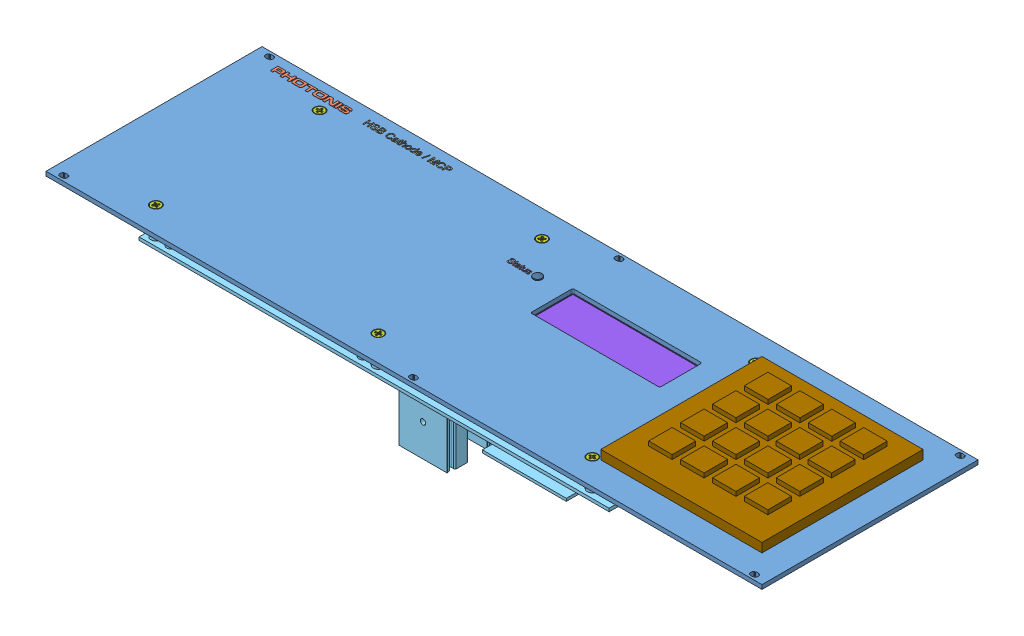
SolidWorks assembly MLA-0387-M0, configuration Default. Lengths in mm.
Overall size (426.52 63.69 128.7).
25 component instances, 13 part files, 41 mates.
Components (placement in the parent):
- MLA-0387-M11-1: MLA-0387-M11 [Default] at (-7.6092 -164.7802 590.2232) size (426.52 2.65 128.7)
  - MLA-0387-M1-1: MLA-0387-M1 [Default] at (-7.8975 -174.6729 597.0963) size (426.52 2.5 128.7)
  - LOGO PHOTONIS-1: LOGO PHOTONIS [Default] at (9.7425 205.5771 259.7963) x (1 0 0) z (0 1 0) size (45.16 4.45 0.15)
  - Kathode-MCP text-1: Kathode-MCP text [Default] at (64.2855 205.4271 259.8791) size (50 0.1 4.1)
  - Status text-1: Status text [Default] at (178.1079 205.4271 288.0463) size (13.33 0.1 3.59)
- MLA-0387-P0-PB1-2: MLA-0387-P0-PB1 [Default] at (32.2133 24.1369 958.3196) x (1 0 0) z (0 1 0) size (280 107.5 53.19)
- pan_head_phillip_M2x4-1: pan_head_phillip_M2x4 [Default] at (196.4634 28.7469 857.3195) x (1 0 0) z (0 0 1) size (4 9.78 4)
- pan_head_phillip_M2x4-2: pan_head_phillip_M2x4 [Default] at (289.4634 28.7469 857.3195) x (-1 0 0) z (0 0 -1) size (4 9.78 4)
- pan_head_phillip_M2x4-3: pan_head_phillip_M2x4 [Default] at (196.4634 28.7469 912.3195) x (1 0 0) z (0 0 1) size (4 9.78 4)
- pan_head_phillip_M2x4-4: pan_head_phillip_M2x4 [Default] at (289.4634 28.7469 912.3195) x (1 0 0) z (0 0 1) size (4 9.78 4)
- SCREW_ISO 7046-1: SCREW_ISO 7046 [VIJAK M 3x 10] at (37.2133 40.6469 855.8195) x (0 -1 0) z (0 0 1) size (10 5.6 5.6)
- SCREW_ISO 7046-2: SCREW_ISO 7046 [VIJAK M 3x 10] at (37.2133 40.6469 953.3195) x (0 -1 0) z (-0.86006 0 -0.510193) size (10 5.6 5.6)
- SCREW_ISO 7046-3: SCREW_ISO 7046 [VIJAK M 3x 10] at (169.7133 40.5604 953.3195) x (0 -1 0) z (0.989385 0 -0.145321) size (10 5.6 5.6)
- SCREW_ISO 7046-4: SCREW_ISO 7046 [VIJAK M 3x 10] at (169.7133 40.6469 855.8195) x (0 -1 0) z (0.648115 0 0.761542) size (10 5.6 5.6)
- SCREW_ISO 7046-5: SCREW_ISO 7046 [VIJAK M 3x 10] at (297.2133 40.6469 855.8195) x (0 -1 0) z (0 0 1) size (10 5.6 5.6)
- SCREW_ISO 7046-6: SCREW_ISO 7046 [VIJAK M 3x 10] at (297.2133 40.6469 953.3195) x (0 -1 0) z (0 0 1) size (10 5.6 5.6)
- NHD-0420D3Z-FL-GBW-V3-3: NHD-0420D3Z-FL-GBW-V3 [Default] at (193.9634 27.1469 914.8195) x (1 0 0) z (0 1 0) size (98 60 10.6)
- Storm_7016010-4: Storm_7016010 [Default] at (301.3033 40.6469 952.3695) x (1 0 0) z (0 1 0) size (96 96 22)
- PLW5-500-1: PLW5-500 [Default] at (188.2133 40.6469 876.9095) size (5.25 13.97 5.07)
- MLA-0387-M7-1: MLA-0387-M7 [Default] at (41.2132 32.1469 958.3196) x (1 0 0) z (0 0 1) size (124.5 3 107.5)
- M2_5x8_Pan_head-1: M2_5x8_Pan_head [Default] at (46.2132 35.1469 855.8196) x (0 -1 0) z (-0.996671 0 -0.081529) size (13.3 7.99 5.14)
- M2_5x8_Pan_head-2: M2_5x8_Pan_head [Default] at (46.2132 35.1469 953.3196) x (0 -1 0) z (0.171735 0 0.985143) size (13.3 7.99 5.14)
- M2_5x8_Pan_head-3: M2_5x8_Pan_head [Default] at (160.7132 35.1469 953.3196) x (0 -1 0) z (0.996977 0 0.077698) size (13.3 7.99 5.14)
- M2_5x8_Pan_head-4: M2_5x8_Pan_head [Default] at (160.7132 35.1469 855.8196) x (0 -1 0) z (-0.397383 0 0.917653) size (13.3 7.99 5.14)
- MLA-0387-C0-1: MLA-0387-C0 [Default] at (-1.6596 221.2858 390.662)
Mates (geometry in assembly coordinates):
- Concentric32: concentric aligned: cone of MLA-0387-M11-1/MLA-0387-M1-1 through (37.2133 40.6469 855.8195) axis (0 -1 0); cone of SCREW_ISO 7046-1 through (37.2133 39.1469 855.8195) axis (0 -1 0)
- Coincident46: coincident aligned: plane of MLA-0387-M11-1/MLA-0387-M1-1 through (-7.4263 40.6469 884.2436) normal (0 1 0); plane of SCREW_ISO 7046-1 through (37.2133 40.6469 855.8195) normal (0 1 0)
- Concentric33: concentric aligned: cone of MLA-0387-M11-1/MLA-0387-M1-1 through (37.2133 40.6469 953.3195) axis (0 -1 0); cone of SCREW_ISO 7046-2 through (37.2133 39.1469 953.3195) axis (0 -1 0)
- Coincident47: coincident aligned: plane of MLA-0387-M11-1/MLA-0387-M1-1 through (-7.4263 40.6469 884.2436) normal (0 1 0); plane of SCREW_ISO 7046-2 through (37.2133 40.6469 953.3195) normal (0 1 0)
- Coincident48: coincident: circle of MLA-0387-M11-1/MLA-0387-M1-1; cone of SCREW_ISO 7046-3 through (169.7133 39.0604 953.3195) axis (0 -1 0)
- Concentric34: concentric aligned: cone of MLA-0387-M11-1/MLA-0387-M1-1 through (169.7133 40.6469 855.8195) axis (0 -1 0); cone of SCREW_ISO 7046-4 through (169.7133 39.1469 855.8195) axis (0 -1 0)
- Coincident49: coincident aligned: plane of MLA-0387-M11-1/MLA-0387-M1-1 through (-7.4263 40.6469 884.2436) normal (0 1 0); plane of SCREW_ISO 7046-4 through (169.7133 40.6469 855.8195) normal (0 1 0)
- Concentric35: concentric aligned: cone of MLA-0387-M11-1/MLA-0387-M1-1 through (297.2133 40.6469 855.8195) axis (0 -1 0); cone of SCREW_ISO 7046-5 through (297.2133 39.1469 855.8195) axis (0 -1 0)
- Coincident50: coincident aligned: plane of MLA-0387-M11-1/MLA-0387-M1-1 through (-7.4263 40.6469 884.2436) normal (0 1 0); plane of SCREW_ISO 7046-5 through (297.2133 40.6469 855.8195) normal (0 1 0)
- Concentric36: concentric aligned: cone of MLA-0387-M11-1/MLA-0387-M1-1 through (297.2133 40.6469 953.3195) axis (0 -1 0); cone of SCREW_ISO 7046-6 through (297.2133 39.1469 953.3195) axis (0 -1 0)
- Coincident51: coincident aligned: plane of MLA-0387-M11-1/MLA-0387-M1-1 through (-7.4263 40.6469 884.2436) normal (0 1 0); plane of SCREW_ISO 7046-6 through (297.2133 40.6469 953.3195) normal (0 1 0)
- Coincident60: coincident aligned: plane of MLA-0387-M11-1/MLA-0387-M1-1 through (-7.4263 38.1469 884.2436) normal (0 -1 0); circle of MLA-0387-P0-PB1-2
- Concentric37: concentric aligned: cylinder of MLA-0387-M11-1/MLA-0387-M1-1 through (169.7133 40.6469 855.8195) axis (0 -1 0) radius 1.75; cylinder of MLA-0387-P0-PB1-2 through (169.7133 31.7469 855.8195) axis (0 -1 0) radius 3
- Concentric38: concentric aligned: cylinder of MLA-0387-M11-1/MLA-0387-M1-1 through (297.2133 40.6469 953.3195) axis (0 -1 0) radius 1.75; cylinder of MLA-0387-P0-PB1-2 through (297.2133 31.7469 953.3195) axis (0 -1 0) radius 3
- Coincident54: coincident aligned: circle of MLA-0387-P0-PB1-2; plane of NHD-0420D3Z-FL-GBW-V3-3 through (193.9634 27.1469 914.8195) normal (0 -1 0)
- Concentric39: concentric aligned: cylinder of NHD-0420D3Z-FL-GBW-V3-3 through (196.4634 27.1469 857.3195) axis (0 1 0) radius 1.25; cylinder of MLA-0387-P0-PB1-2 through (196.4634 22.7469 857.3195) axis (0 1 0) radius 2.175
- Concentric40: concentric aligned: cylinder of MLA-0387-P0-PB1-2 through (289.4634 22.7469 857.3195) axis (0 1 0) radius 2.175; cylinder of NHD-0420D3Z-FL-GBW-V3-3 through (289.4634 27.1469 857.3195) axis (0 1 0) radius 1.25
- Concentric41: concentric anti-aligned: cylinder of pan_head_phillip_M2x4-1 through (196.4634 30.5319 857.3195) axis (0 -1 0) radius 2; cylinder of NHD-0420D3Z-FL-GBW-V3-3 through (196.4634 27.1469 857.3195) axis (0 1 0) radius 1.25
- Coincident55: coincident anti-aligned: plane of pan_head_phillip_M2x4-1 through (196.4634 28.7469 857.3195) normal (0 -1 0); plane of NHD-0420D3Z-FL-GBW-V3-3 through (193.9634 28.7469 914.8195) normal (0 1 0)
- Concentric42: concentric anti-aligned: cylinder of pan_head_phillip_M2x4-2 through (289.4634 30.5319 857.3195) axis (0 -1 0) radius 2; cylinder of NHD-0420D3Z-FL-GBW-V3-3 through (289.4634 27.1469 857.3195) axis (0 1 0) radius 1.25
- Coincident56: coincident anti-aligned: plane of pan_head_phillip_M2x4-2 through (289.4634 28.7469 857.3195) normal (0 -1 0); plane of NHD-0420D3Z-FL-GBW-V3-3 through (193.9634 28.7469 914.8195) normal (0 1 0)
- Concentric43: concentric anti-aligned: cylinder of pan_head_phillip_M2x4-4 through (289.4634 30.5319 912.3195) axis (0 -1 0) radius 2; cylinder of NHD-0420D3Z-FL-GBW-V3-3 through (289.4634 27.1469 912.3195) axis (0 1 0) radius 1.25
- Coincident57: coincident anti-aligned: plane of pan_head_phillip_M2x4-4 through (289.4634 28.7469 912.3195) normal (0 -1 0); plane of NHD-0420D3Z-FL-GBW-V3-3 through (193.9634 28.7469 914.8195) normal (0 1 0)
- Concentric44: concentric anti-aligned: cylinder of pan_head_phillip_M2x4-3 through (196.4634 30.5319 912.3195) axis (0 -1 0) radius 2; cylinder of NHD-0420D3Z-FL-GBW-V3-3 through (196.4634 27.1469 912.3195) axis (0 1 0) radius 1.25
- Coincident58: coincident anti-aligned: plane of pan_head_phillip_M2x4-3 through (196.4634 28.7469 912.3195) normal (0 -1 0); plane of NHD-0420D3Z-FL-GBW-V3-3 through (193.9634 28.7469 914.8195) normal (0 1 0)
- Concentric45: concentric anti-aligned: circle of MLA-0387-M11-1/MLA-0387-M1-1; cylinder of Storm_7016010-4 through (381.3033 26.6469 936.3695) axis (0 1 0) radius 1.5
- Concentric46: concentric anti-aligned: circle of MLA-0387-M11-1/MLA-0387-M1-1; cylinder of Storm_7016010-4 through (317.3033 26.6469 872.3695) axis (0 1 0) radius 1.5
- Coincident61: coincident anti-aligned: plane of MLA-0387-M11-1/MLA-0387-M1-1 through (-7.4263 40.6469 884.2436) normal (0 1 0); plane of Storm_7016010-4 through (301.3033 40.6469 952.3695) normal (0 -1 0)
- Concentric47: concentric aligned: cylinder of MLA-0387-M11-1/MLA-0387-M1-1 through (188.2133 30.6469 876.9095) axis (0 1 0) radius 1.98; cylinder of PLW5-500-1 through (188.2133 29.1325 876.9095) axis (0 1 0) radius 1.9304
- Coincident62: coincident aligned: plane of MLA-0387-M11-1/MLA-0387-M1-1 through (-7.4263 40.6469 884.2436) normal (0 1 0); circle of PLW5-500-1
- Concentric48: concentric anti-aligned: circle of MLA-0387-P0-PB1-2; cylinder of MLA-0387-M7-1 through (46.2132 32.1469 855.8196) axis (0 1 0) radius 1.5
- Concentric49: concentric anti-aligned: cylinder of MLA-0387-P0-PB1-2 through (160.7132 20.2987 953.3196) axis (0 -1 0) radius 1.0065; cylinder of MLA-0387-M7-1 through (160.7132 32.1469 953.3196) axis (0 1 0) radius 1.5
- Coincident63: coincident anti-aligned: plane of MLA-0387-P0-PB1-2 through (163.2632 32.1469 953.3196) normal (0 1 0); plane of MLA-0387-M7-1 through (41.2132 32.1469 958.3196) normal (0 -1 0)
- Concentric50: concentric anti-aligned: cylinder of MLA-0387-P0-PB1-2 through (46.2132 20.2987 855.8196) axis (0 -1 0) radius 1.0065; cylinder of M2_5x8_Pan_head-1 through (46.2132 29.7061 855.8196) axis (0 1 0) radius 1
- Coincident64: coincident anti-aligned: plane of MLA-0387-M7-1 through (41.2132 35.1469 958.3196) normal (0 1 0); plane of M2_5x8_Pan_head-1 through (48.0007 35.1469 855.9659) normal (0 -1 0)
- Concentric51: concentric anti-aligned: cylinder of MLA-0387-P0-PB1-2 through (46.2132 20.2987 953.3196) axis (0 -1 0) radius 1.0065; cylinder of M2_5x8_Pan_head-2 through (46.2132 29.7061 953.3196) axis (0 1 0) radius 1
- Coincident65: coincident anti-aligned: plane of MLA-0387-M7-1 through (41.2132 35.1469 958.3196) normal (0 1 0); plane of M2_5x8_Pan_head-2 through (45.9052 35.1469 951.5528) normal (0 -1 0)
- Concentric52: concentric anti-aligned: cylinder of MLA-0387-P0-PB1-2 through (160.7132 20.2987 953.3196) axis (0 -1 0) radius 1.0065; cylinder of M2_5x8_Pan_head-3 through (160.7132 29.7061 953.3196) axis (0 1 0) radius 1
- Coincident66: coincident anti-aligned: plane of MLA-0387-M7-1 through (41.2132 35.1469 958.3196) normal (0 1 0); plane of M2_5x8_Pan_head-3 through (158.9251 35.1469 953.1803) normal (0 -1 0)
- Concentric53: concentric anti-aligned: cylinder of MLA-0387-P0-PB1-2 through (160.7132 20.2987 855.8196) axis (0 -1 0) radius 1.0065; cylinder of M2_5x8_Pan_head-4 through (160.7132 29.7061 855.8196) axis (0 1 0) radius 1
- Coincident67: coincident anti-aligned: plane of MLA-0387-M7-1 through (41.2132 35.1469 958.3196) normal (0 1 0); plane of M2_5x8_Pan_head-4 through (161.4259 35.1469 854.1738) normal (0 -1 0)
